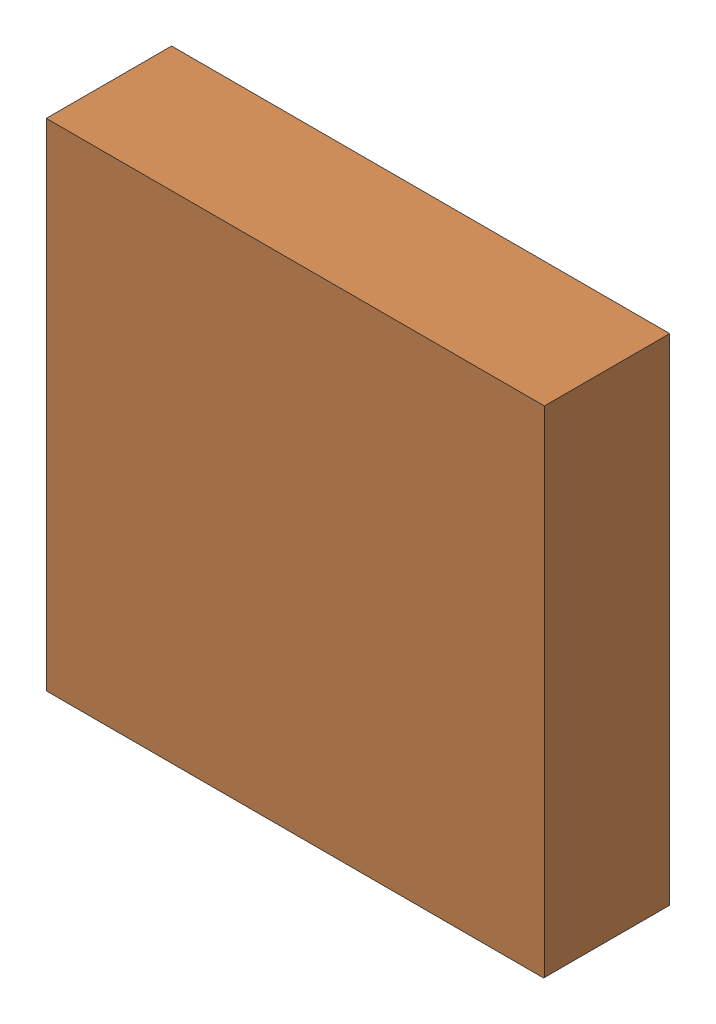
SolidWorks assembly U3, configuration 默认. Lengths in mm.
Overall size (3.19 3.17 0.82).
4 component instances, 2 part files, 0 mates.
Components (placement in the parent):
- 6641441328-1: 6641441328.stp [默认] at (12.1608 18.3998 -2.7339) x (-1 0 0) z (0 0 -1) size (0.2 0.2 0.01)
  - Cylinder-22-1: Cylinder-22 [默认] at origin size (0.2 0.2 0.01)
- 6641441568-1: 6641441568.stp [默认] at (10.9 17.0875 -2.7339) size (3.19 3.17 0.81)
  - Extruded-21-1: Extruded-21 [默认] at origin size (3.19 3.17 0.81)
